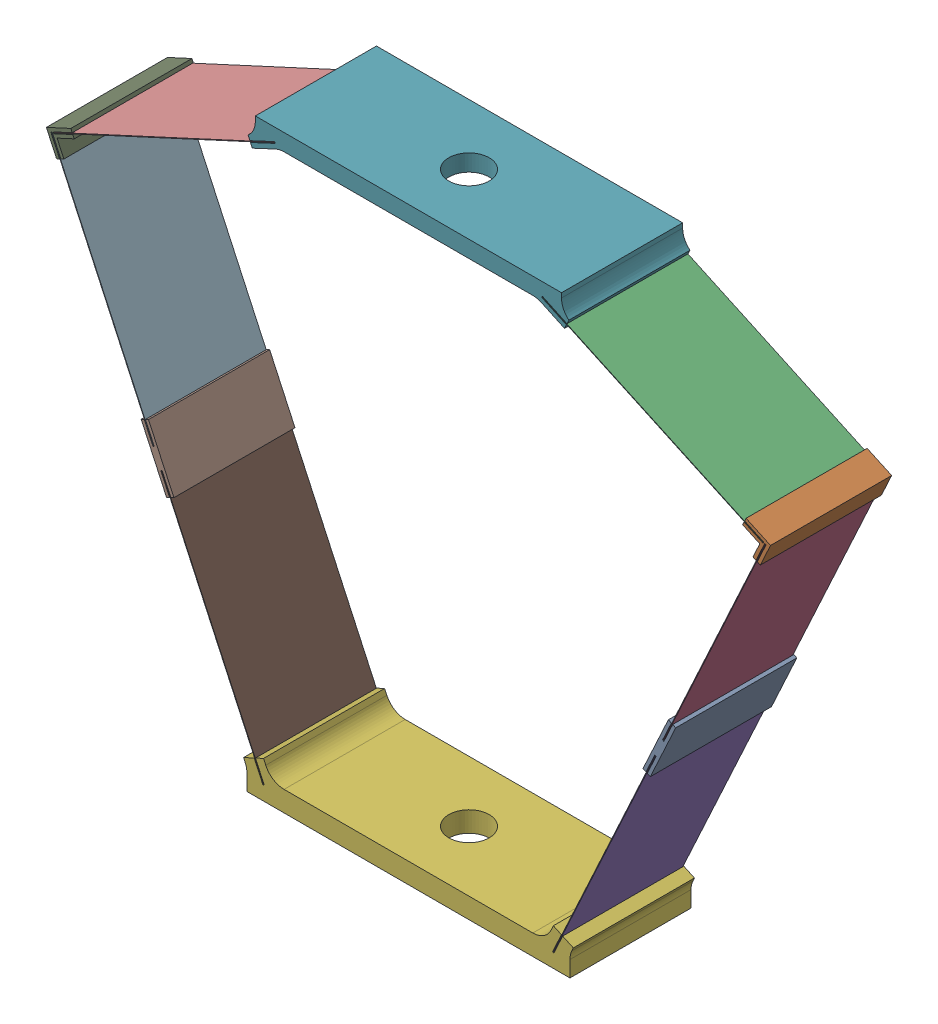
SolidWorks assembly jumper assembly jelle, configuration Default. Lengths in mm.
Overall size (179.36 145.95 30).
12 component instances, 5 part files, 32 mates.
Components (placement in the parent):
- Connect180-1: Connect180 [Default] at (25.4957 56.3406 -9.997) x (0.907924 -0.419135 0) z (0 0 1) size (2 15 30)
- Connect90-1: Connect90 [Default] at (51.2726 112.1779 -9.997) x (0.907924 -0.419135 0) z (0 0 1) size (6.68 6.03 30)
- Flexure-1: Flexure [Default] at (23.8306 125.9201 5.003) x (0 0 -1) z (0.419135 0.907924 0) size (30 60 0.15)
- Flexure-2: Flexure [Default] at (39.163 85.8272 5.003) x (0 0 1) z (-0.907924 0.419135 0) size (30 60 0.15)
- Flexure-3: Flexure [Default] at (11.9192 26.8121 5.003) x (0 0 1) z (-0.907924 0.419135 0) size (30 60 0.15)
- Base-2: Base [Default] at (-36.6509 -1.4985 -9.997) size (81.68 9.16 30)
- Top-2: Top [Default] at (-36.6509 139.8556 -9.997) x (-1 0 0) z (0 0 1) size (79.47 7.28 30)
- Connect180-2: Connect180 [Default] at (-98.7976 56.3406 -9.997) x (0.907924 0.419135 0) z (0 0 1) size (2 15 30)
- Connect90-2: Connect90 [Default] at (-124.5744 112.1779 20.003) x (-0.907924 -0.419135 0) z (0 0 -1) size (6.68 6.03 30)
- Flexure-4: Flexure [Default] at (-97.1325 125.9201 5.003) x (0 0 1) z (-0.419135 0.907924 0) size (30 60 0.15)
- Flexure-5: Flexure [Default] at (-85.2211 26.8121 5.003) x (0 0 -1) z (0.907924 0.419135 0) size (30 60 0.15)
- Flexure-6: Flexure [Default] at (-112.3741 85.8691 5.003) x (0 0 1) z (-0.907924 -0.419135 0) size (30 60 0.15)
Mates (geometry in assembly coordinates):
- Coincident4: coincident aligned: plane of Connect180-1 through (25.4957 56.3406 20.003) normal (0 0 1); plane of Flexure-3 through (24.3571 54.1127 20.003) normal (0 0 1)
- Distance7: distance = 0.075 mm anti-aligned: plane of Connect180-1 through (25.3369 56.414 20.003) normal (0.907924 -0.419135 0); plane of Flexure-3 through (11.7831 26.875 5.003) normal (-0.907924 0.419135 0)
- Distance2: distance = 0.2 mm anti-aligned: plane of Connect180-1 through (24.5317 54.2524 20.003) normal (-0.419135 -0.907924 0); plane of Flexure-3 through (24.3571 54.1127 -9.997) normal (0.419135 0.907924 0)
- Distance8: distance = 0.075 mm anti-aligned: plane of Connect180-1 through (25.3369 56.414 20.003) normal (0.907924 -0.419135 0); plane of Flexure-2 through (39.0268 85.8901 5.003) normal (-0.907924 0.419135 0)
- Coincident8: coincident aligned: plane of Connect180-1 through (25.4957 56.3406 20.003) normal (0 0 1); plane of Flexure-2 through (51.6009 113.1278 20.003) normal (0 0 1)
- Distance3: distance = 0.2 mm anti-aligned: plane of Connect180-1 through (26.4597 58.4288 20.003) normal (0.419135 0.907924 0); plane of Flexure-2 through (26.4528 58.6523 -9.997) normal (-0.419135 -0.907924 0)
- Coincident10: coincident aligned: plane of Connect90-1 through (51.2726 112.1779 20.003) normal (0 0 1); plane of Flexure-2 through (51.6009 113.1278 20.003) normal (0 0 1)
- Distance9: distance = 0.075 mm anti-aligned: plane of Connect90-1 through (51.1137 112.2513 20.003) normal (0.907924 -0.419135 0); plane of Flexure-2 through (39.0268 85.8901 5.003) normal (-0.907924 0.419135 0)
- Distance4: distance = 0.2 mm anti-aligned: plane of Connect90-1 through (51.7755 113.2674 20.003) normal (-0.419135 -0.907924 0); plane of Flexure-2 through (51.6009 113.1278 -9.997) normal (0.419135 0.907924 0)
- Distance10: distance = 0.075 mm anti-aligned: plane of Connect90-1 through (51.7755 113.2674 20.003) normal (-0.419135 -0.907924 0); plane of Flexure-1 through (23.8935 126.0563 5.003) normal (0.419135 0.907924 0)
- Coincident14: coincident aligned: plane of Connect90-1 through (51.2726 112.1779 20.003) normal (0 0 1); plane of Flexure-1 through (-3.3442 138.6304 20.003) normal (0 0 1)
- Distance5: distance = 0.2 mm anti-aligned: plane of Connect90-1 through (50.8413 112.377 20.003) normal (-0.907924 0.419135 0); plane of Flexure-1 through (51.1312 113.4823 20.003) normal (0.907924 -0.419135 0)
- Distance11: distance = 0.075 mm anti-aligned: plane of Flexure-3 through (11.7831 26.875 5.003) normal (-0.907924 0.419135 0); plane of Base-2 through (-7.591 -14.9138 20.003) normal (0.907924 -0.419135 0)
- Coincident17: coincident aligned: plane of Flexure-3 through (24.3571 54.1127 20.003) normal (0 0 1); plane of Base-2 through (-36.6509 -1.4985 20.003) normal (0 0 1)
- Distance12: distance = 0.2 mm anti-aligned: plane of Flexure-3 through (-0.791 -0.3627 -9.997) normal (-0.419135 -0.907924 0); plane of Base-2 through (-30.0029 12.9024 20.003) normal (0.419135 0.907924 0)
- Concentric1: concentric anti-aligned: cylinder of Base-2 through (-36.6509 -8.9697 5.003) axis (0 1 0) radius 5; cylinder of Top-2 through (-36.6509 167.7851 5.003) axis (0 -1 0) radius 5
- Coincident19: coincident aligned: plane of Base-2 through (-36.6509 -1.4985 20.003) normal (0 0 1); plane of Top-2 through (-36.6509 139.8556 20.003) normal (0 0 1)
- Distance14: distance = 0.075 mm anti-aligned: plane of Flexure-5 through (-85.0849 26.875 5.003) normal (0.907924 0.419135 0); plane of Base-2 through (-65.7109 -14.9138 20.003) normal (-0.907924 -0.419135 0)
- Coincident22: coincident aligned: plane of Base-2 through (-36.6509 -1.4985 20.003) normal (0 0 1); plane of Flexure-5 through (-97.659 54.1127 20.003) normal (0 0 1)
- Distance15: distance = 0.2 mm anti-aligned: plane of Flexure-5 through (-72.5109 -0.3627 20.003) normal (0.419135 -0.907924 0); plane of Base-2 through (-43.299 12.9024 20.003) normal (-0.419135 0.907924 0)
- Distance16: distance = 0.075 mm anti-aligned: plane of Connect180-2 through (-98.6387 56.414 20.003) normal (-0.907924 -0.419135 0); plane of Flexure-5 through (-85.0849 26.875 5.003) normal (0.907924 0.419135 0)
- Coincident25: coincident aligned: plane of Base-2 through (-36.6509 -1.4985 20.003) normal (0 0 1); plane of Connect180-2 through (-98.7976 56.3406 20.003) normal (0 0 1)
- Distance17: distance = 0.2 mm anti-aligned: plane of Flexure-5 through (-97.659 54.1127 20.003) normal (-0.419135 0.907924 0); plane of Connect180-2 through (-97.8336 54.2524 20.003) normal (0.419135 -0.907924 0)
- Distance18: distance = 0.075 mm anti-aligned: plane of Connect180-2 through (-98.9565 56.2673 20.003) normal (0.907924 0.419135 0); plane of Flexure-6 through (-112.5103 85.8062 5.003) normal (-0.907924 -0.419135 0)
- Coincident28: coincident aligned: plane of Connect180-2 through (-98.7976 56.3406 20.003) normal (0 0 1); plane of Flexure-6 through (-125.0844 113.0439 20.003) normal (0 0 1)
- Distance19: distance = 0.2 mm anti-aligned: plane of Flexure-6 through (-99.9362 58.5685 -9.997) normal (0.419135 -0.907924 0); plane of Connect180-2 through (-99.7616 58.4288 20.003) normal (-0.419135 0.907924 0)
- Coincident31: coincident aligned: plane of Base-2 through (-36.6509 -1.4985 -9.997) normal (0 0 -1); plane of Connect90-2 through (-124.5744 112.1779 -9.997) normal (0 0 -1)
- Distance21: distance = 0.075 mm anti-aligned: plane of Connect90-2 through (-124.7333 112.1046 -9.997) normal (0.907924 0.419135 0); plane of Flexure-6 through (-112.5103 85.8062 5.003) normal (-0.907924 -0.419135 0)
- Distance22: distance = 0.2 mm anti-aligned: plane of Connect90-2 through (-125.0774 113.2674 -9.997) normal (0.419135 -0.907924 0); plane of Flexure-6 through (-125.0844 113.0439 -9.997) normal (-0.419135 0.907924 0)
- Coincident34: coincident: plane of Connect90-2 through (-124.5744 112.1779 -9.997) normal (0 0 -1); plane of Flexure-4 through (-69.981 138.6196 -9.997) normal (0 0 -1)
- Distance23: distance = 0.075 mm: plane of Flexure-4 through (-97.1954 126.0563 5.003) normal (-0.419135 0.907924 0); plane of Connect90-2 through (-125.0774 113.2674 -9.997) normal (0.419135 -0.907924 0)
- Distance25: distance = 0.2 mm anti-aligned: plane of Connect90-2 through (-124.1432 112.377 -9.997) normal (0.907924 0.419135 0); plane of Flexure-4 through (-124.4331 113.4823 -9.997) normal (-0.907924 -0.419135 0)
